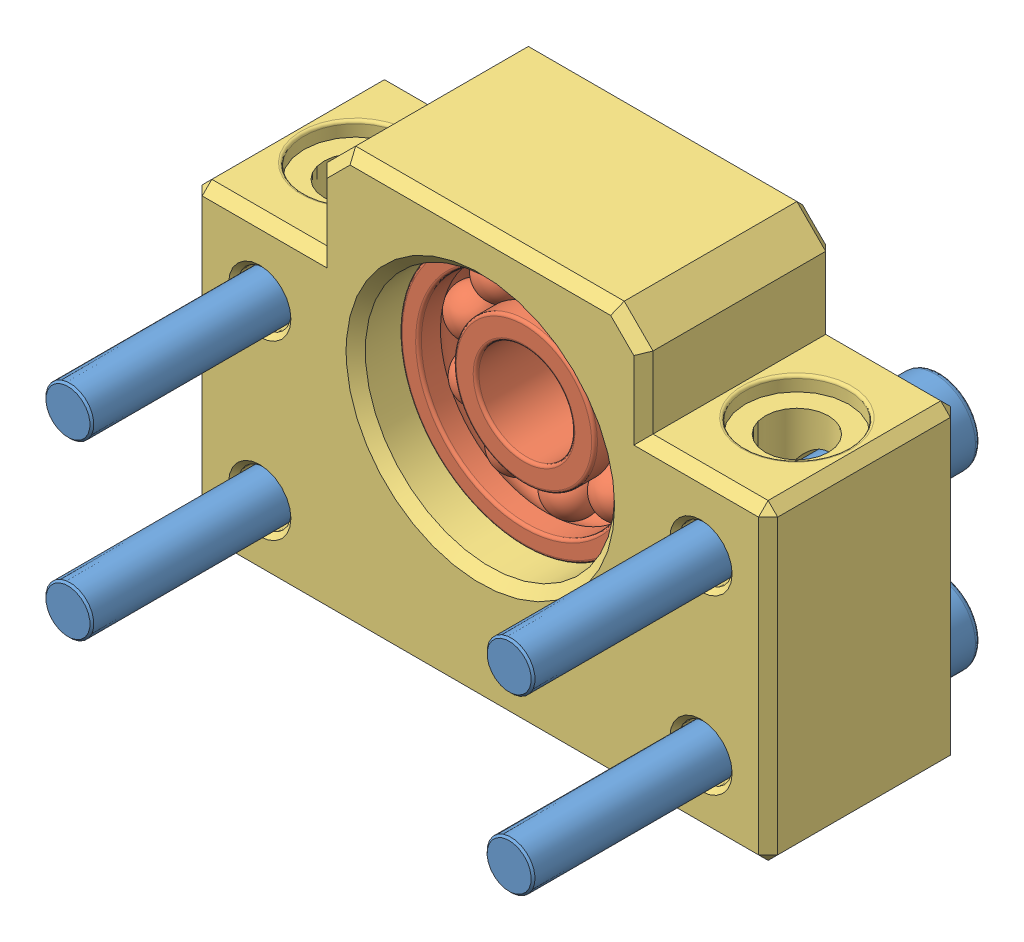
SolidWorks assembly BF12 BALLSCREW END SUPPORT, configuration Default. Lengths in mm.
Overall size (60 43 45).
6 component instances, 3 part files, 9 mates.
Components (placement in the parent):
- hexagon socket head cap screws gb1-5: hexagon socket head cap screws gb1 [GB_FASTENER_SCREWS_HSHCS M5X40-N] at (-35.8001 -13.9554 -13.2224) x (0 0 1) z (0.923728 -0.383049 0) size (45 8.5 8.5)
- hexagon socket head cap screws gb1-6: hexagon socket head cap screws gb1 [GB_FASTENER_SCREWS_HSHCS M5X40-N] at (10.1999 -13.9554 -13.2224) x (0 0 1) z (0.983147 -0.182814 0) size (45 8.5 8.5)
- hexagon socket head cap screws gb1-7: hexagon socket head cap screws gb1 [GB_FASTENER_SCREWS_HSHCS M5X40-N] at (-35.8001 4.0446 -13.2224) x (0 0 1) z (-0.994932 -0.100553 0) size (45 8.5 8.5)
- hexagon socket head cap screws gb1-8: hexagon socket head cap screws gb1 [GB_FASTENER_SCREWS_HSHCS M5X40-N] at (10.1999 4.0446 -13.2224) x (0 0 1) z (-0.383049 -0.923728 0) size (45 8.5 8.5)
- 6000-Bearing-4: 6000-Bearing [Default] at (-12.8001 4.0446 -0.7724) x (0.978353 -0.206941 0) z (0 0 1) size (26 26 8)
- BF12-1-4: BF12-1 [Default] at (-12.8001 22.0446 -8.2224) size (60 43 20)
Mates (geometry in assembly coordinates):
- Concentric2130: concentric: cylinder of assembly; cylinder of assembly; cylinder of BF12-1-4 through (-35.8001 -13.9554 11.7776) axis (0 0 -1) radius 2.75; cylinder of hexagon socket head cap screws gb1-5 through (-35.8001 -13.9554 31.7776) axis (0 0 -1) radius 2.5
- Coincident4169: coincident: plane of assembly; plane of assembly; plane of BF12-1-4 through (17.1999 -20.9554 -8.2224) normal (0 0 -1); plane of hexagon socket head cap screws gb1-5 through (-35.8001 -13.9554 -8.2224) normal (0 0 1)
- Concentric2131: concentric: cylinder of assembly; cylinder of assembly; cylinder of BF12-1-4 through (10.1999 -13.9554 11.7776) axis (0 0 -1) radius 2.75; cylinder of hexagon socket head cap screws gb1-6 through (10.1999 -13.9554 31.7776) axis (0 0 -1) radius 2.5
- Coincident4170: coincident: plane of assembly; plane of assembly; plane of BF12-1-4 through (17.1999 -20.9554 -8.2224) normal (0 0 -1); plane of hexagon socket head cap screws gb1-6 through (10.1999 -13.9554 -8.2224) normal (0 0 1)
- Concentric2132: concentric: circle of assembly; circle of assembly; circle of BF12-1-4; circle of hexagon socket head cap screws gb1-7
- Coincident4171: coincident: plane of assembly; plane of assembly; plane of BF12-1-4 through (17.1999 -20.9554 -8.2224) normal (0 0 -1); plane of hexagon socket head cap screws gb1-7 through (-35.8001 4.0446 -8.2224) normal (0 0 1)
- Coincident4172: coincident: plane of assembly; plane of assembly; plane of BF12-1-4 through (17.1999 -20.9554 -8.2224) normal (0 0 -1); plane of hexagon socket head cap screws gb1-8 through (10.1999 4.0446 -8.2224) normal (0 0 1)
- Concentric2133: concentric: cone of assembly; cylinder of assembly; cone of BF12-1-4 through (10.1999 4.0446 -7.7224) axis (0 0 1); cylinder of hexagon socket head cap screws gb1-8 through (10.1999 4.0446 31.7776) axis (0 0 -1) radius 2.5
- Concentric2134: concentric: cylinder of assembly; cylinder of assembly; cylinder of BF12-1-4 through (-12.8001 4.0446 11.7776) axis (0 0 -1) radius 13; cylinder of 6000-Bearing-4 through (-12.8001 4.0446 7.2276) axis (0 0 -1) radius 13
